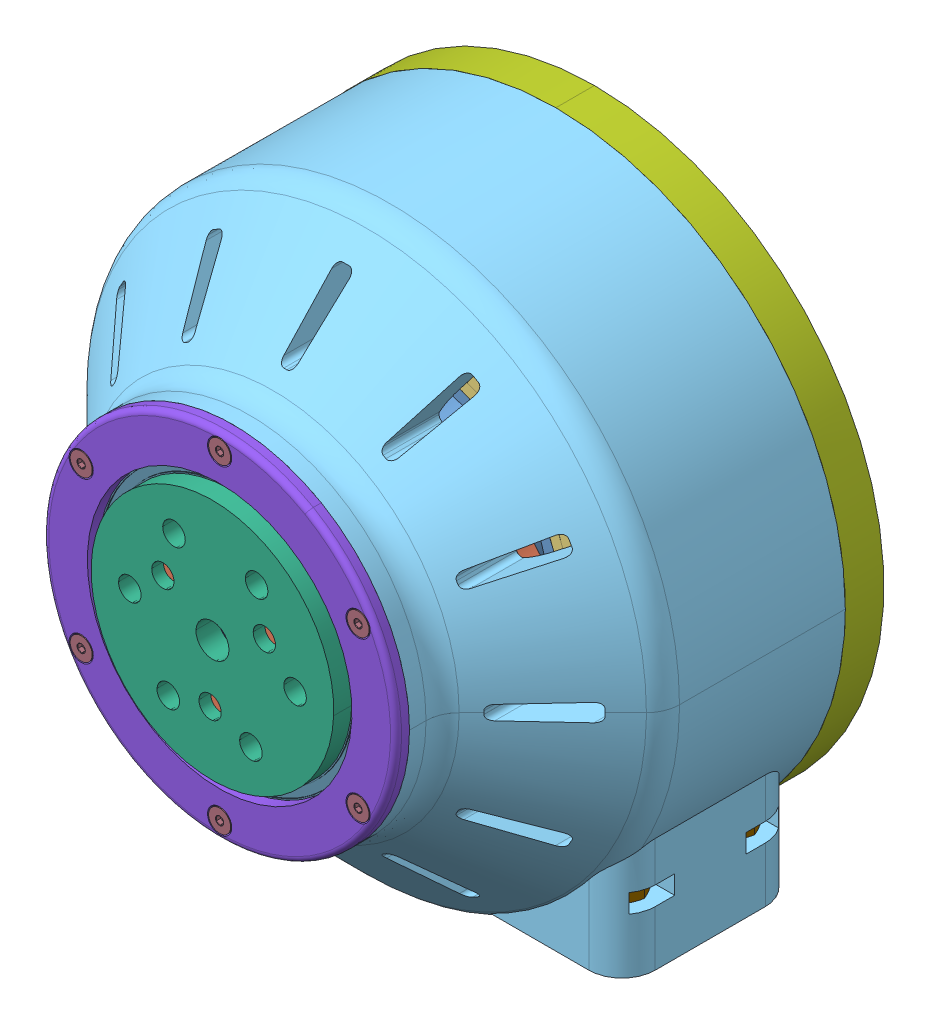
SolidWorks assembly sprydrive 9235, configuration Default. Lengths in mm.
Overall size (130.11 130.11 75.41).
71 component instances, 27 part files, 0 mates.
Components (placement in the parent):
- sprydrive 9235.STEP-1: sprydrive 9235.STEP [Default] at origin size (130.11 130.11 75.41)
  - MOTOR BACK HOUSING REV01.STEP-1: MOTOR BACK HOUSING REV01.STEP [Default] at (0 0 6) x (0.707107 0.707107 0) z (-0.707107 0.707107 0) size (92 25.2 92)
  - MOTOR ROTOR REV01_9235.STEP-1: MOTOR ROTOR REV01_9235.STEP [Default] at (0 0 6.3) x (0.001555 -0.999999 0) z (-0.999999 -0.001555 0) size (92 31.21 92)
  - MOTOR STATOR REV01.STEP-1: MOTOR STATOR REV01.STEP [Default] at (0 0 7.2) x (-0.996782 0.080159 0) z (0.080159 0.996782 0) size (81.2 19.01 81.2)
  - MOTOR SHAFT REV01_9235.STEP-1: MOTOR SHAFT REV01_9235.STEP [Default] at (0 0 3.5) x (-0.001555 0.999999 0) z (0.999999 0.001555 0) size (19.64 47.51 18.94)
  - FRAME REV07_9235.STEP-1: FRAME REV07_9235.STEP [Default] at origin size (105 105 58.55)
  - OUTPUT PLATE REV05.STEP-1: OUTPUT PLATE REV05.STEP [Default] at (0 0 58.225) x (-0.999207 0.039825 0) z (0 0 1) size (44 44 11.85)
  - BACK PLATE REV05.STEP-1: BACK PLATE REV05.STEP [Default] x (-1 0 0) z (0 -1 0) size (105 7 105)
  - BEARING COVER REV04.STEP-1: BEARING COVER REV04.STEP [Default] at (0 0 59) x (-0.5 -0.866025 0) z (0 0 1) size (64 64 2.45)
  - ADAPTER PLATE REV05.STEP-1: ADAPTER PLATE REV05.STEP [Default] at (0 0 37.5) x (-0.999999 -0.001555 0) z (0 0 1) size (37 37 3.17)
  - MAGNET HOLDER REV02.STEP-1: MAGNET HOLDER REV02.STEP [Default] at (0 0 -2) x (0.865247 0.501346 0) z (0 0 -1) size (24 24 5)
  - ENCODER MOUNT REV01.STEP-1: ENCODER MOUNT REV01.STEP [Default] x (-1 0 0) z (0 -1 0) size (35.15 5.5 30)
  - 91294A190_BLACK ALLOY STEEL FLAT-HEAD SOCKET CAP SCREW_91294A190.STEP-1: 91294A190_BLACK ALLOY STEEL FLAT-HEAD SOCKET CAP SCREW_91294A190.STEP [Default] at (-20 0 -6.6) x (-1 0 0) z (0 0 -1) size (8 8 10.01)
  - 91294A190_BLACK ALLOY STEEL FLAT-HEAD SOCKET CAP SCREW_91294A190.STEP-2: 91294A190_BLACK ALLOY STEEL FLAT-HEAD SOCKET CAP SCREW_91294A190.STEP [Default] at (0 20 -6.6) x (-1 0 0) z (0 0 -1) size (8 8 10.01)
  - 91294A190_BLACK ALLOY STEEL FLAT-HEAD SOCKET CAP SCREW_91294A190.STEP-3: 91294A190_BLACK ALLOY STEEL FLAT-HEAD SOCKET CAP SCREW_91294A190.STEP [Default] at (20 0 -6.6) x (-1 0 0) z (0 0 -1) size (8 8 10.01)
  - 93395A144_TYPE 316 SS FLAT-HEAD SOCKET CAP SCREW_93395A144.STEP-1: 93395A144_TYPE 316 SS FLAT-HEAD SOCKET CAP SCREW_93395A144.STEP [Default] at (14.0729 8.125 -12.5) x (-1 0 0) z (0 0 -1) size (4 4 10)
  - 93395A144_TYPE 316 SS FLAT-HEAD SOCKET CAP SCREW_93395A144.STEP-2: 93395A144_TYPE 316 SS FLAT-HEAD SOCKET CAP SCREW_93395A144.STEP [Default] at (-14.0729 8.125 -12.5) x (-1 0 0) z (0 0 -1) size (4 4 10)
  - 93395A144_TYPE 316 SS FLAT-HEAD SOCKET CAP SCREW_93395A144.STEP-3: 93395A144_TYPE 316 SS FLAT-HEAD SOCKET CAP SCREW_93395A144.STEP [Default] at (-14.0729 -8.125 -12.5) x (-1 0 0) z (0 0 -1) size (4 4 10)
  - 93395A144_TYPE 316 SS FLAT-HEAD SOCKET CAP SCREW_93395A144.STEP-4: 93395A144_TYPE 316 SS FLAT-HEAD SOCKET CAP SCREW_93395A144.STEP [Default] at (14.0729 -8.125 -12.5) x (-1 0 0) z (0 0 -1) size (4 4 10)
  - 6808-2RS BEARING DEEP GROOVE 40x52x7 REV02_4668K161.STEP-1: 6808-2RS BEARING DEEP GROOVE 40x52x7 REV02_4668K161.STEP [Default] at (0 0 55.5) x (0.843788 0.536676 0) z (0 0 -1) size (52 52 7)
  - AS5048A-AB-1.0-ND ENCODER BOARD.STEP-1: AS5048A-AB-1.0-ND ENCODER BOARD.STEP [Default] at (0 -6.5 -10) x (-1 0 0) z (0 1 0) size (22 2 28)
  - AS5048A-AB-1.0-ND MAGNET.STEP-1: AS5048A-AB-1.0-ND MAGNET.STEP [Default] at (0 0 -6.5) x (0.996708 0.081075 0) z (0.081075 -0.996708 0) size (6 2.5 6)
  - OUTPUT MOUNTING PLATE REV01.STEP-1: OUTPUT MOUNTING PLATE REV01.STEP [Default] at (0 0 55.05) x (0.465114 -0.885251 0) z (0 0 1) size (35 35 3.17)
  - VERSA PLANET.STEP-1: VERSA PLANET.STEP [Default] at (-8.9927 5.6811 46.35) x (-0.69895 0.715171 0) z (0 0 1) size (16.03 16.01 8)
  - VERSA PLANET.STEP-2: VERSA PLANET.STEP [Default] at (9.4163 4.9473 46.35) x (0.461046 0.887376 0) z (0 0 1) size (16.03 16.01 8)
  - VERSA PLANET.STEP-3: VERSA PLANET.STEP [Default] at (-0.4236 -10.6284 46.35) x (-0.3211 -0.947045 0) z (0 0 1) size (16.03 16.01 8)
  - VERSA RING - MODIFIED.STEP-1: VERSA RING - MODIFIED.STEP [Default] at (0 0 41.6) x (0 1 0) z (0 0 -1) size (42 42 11.32)
  - 93600A455_METRIC TYPE 316 STAINLESS STEEL DOWEL PIN_93600A455.STEP-1: 93600A455_METRIC TYPE 316 STAINLESS STEEL DOWEL PIN_93600A455.STEP [Default] at (-8.9927 5.6811 51.35) x (0 0 -1) z (0.833244 0.552906 0) size (18 4 4)
  - 93600A455_METRIC TYPE 316 STAINLESS STEEL DOWEL PIN_93600A455.STEP-2: 93600A455_METRIC TYPE 316 STAINLESS STEEL DOWEL PIN_93600A455.STEP [Default] at (9.4163 4.9473 51.35) x (0 0 -1) z (0.833244 0.552906 0) size (18 4 4)
  - 93600A455_METRIC TYPE 316 STAINLESS STEEL DOWEL PIN_93600A455.STEP-3: 93600A455_METRIC TYPE 316 STAINLESS STEEL DOWEL PIN_93600A455.STEP [Default] at (-0.4236 -10.6284 51.35) x (0 0 -1) z (-0.663244 0.748403 0) size (18 4 4)
  - 90358A002_METRIC STL ULTRA-LOW-PROFILE SCKT HEAD SCREW_90358A002.STEP-1: 90358A002_METRIC STL ULTRA-LOW-PROFILE SCKT HEAD SCREW_90358A002.STEP [Default] at (0.0241 -15.5 36.675) x (0 0 -1) z (-0.620938 -0.783859 0) size (9.01 5.5 5.5)
  - 90358A002_METRIC STL ULTRA-LOW-PROFILE SCKT HEAD SCREW_90358A002.STEP-2: 90358A002_METRIC STL ULTRA-LOW-PROFILE SCKT HEAD SCREW_90358A002.STEP [Default] at (15.5 0.0241 36.675) x (0 0 -1) z (-0.964603 -0.263707 0) size (9.01 5.5 5.5)
  - 90358A002_METRIC STL ULTRA-LOW-PROFILE SCKT HEAD SCREW_90358A002.STEP-3: 90358A002_METRIC STL ULTRA-LOW-PROFILE SCKT HEAD SCREW_90358A002.STEP [Default] at (-0.0241 15.5 36.675) x (0 0 -1) z (-0.993401 0.11469 0) size (9.01 5.5 5.5)
  - 90358A002_METRIC STL ULTRA-LOW-PROFILE SCKT HEAD SCREW_90358A002.STEP-4: 90358A002_METRIC STL ULTRA-LOW-PROFILE SCKT HEAD SCREW_90358A002.STEP [Default] at (-15.5 -0.0241 36.675) x (0 0 -1) z (-0.942672 -0.333722 0) size (9.01 5.5 5.5)
  - 93395A144_TYPE 316 SS FLAT-HEAD SOCKET CAP SCREW_93395A144.STEP-5: 93395A144_TYPE 316 SS FLAT-HEAD SOCKET CAP SCREW_93395A144.STEP [Default] at (0 29 61) size (4 4 10)
  - 93395A144_TYPE 316 SS FLAT-HEAD SOCKET CAP SCREW_93395A144.STEP-6: 93395A144_TYPE 316 SS FLAT-HEAD SOCKET CAP SCREW_93395A144.STEP [Default] at (25.1147 14.5 61) size (4 4 10)
  - 93395A144_TYPE 316 SS FLAT-HEAD SOCKET CAP SCREW_93395A144.STEP-7: 93395A144_TYPE 316 SS FLAT-HEAD SOCKET CAP SCREW_93395A144.STEP [Default] at (-25.1147 14.5 61) size (4 4 10)
  - 93395A144_TYPE 316 SS FLAT-HEAD SOCKET CAP SCREW_93395A144.STEP-8: 93395A144_TYPE 316 SS FLAT-HEAD SOCKET CAP SCREW_93395A144.STEP [Default] at (25.1147 -14.5 61) size (4 4 10)
  - 94459A110_BRASS HEAT-SET INSERT FOR PLASTIC_94459A110.STEP-1: 94459A110_BRASS HEAT-SET INSERT FOR PLASTIC_94459A110.STEP [Default] at (25.1147 14.5 56.05) x (-0.767549 -0.640991 0) z (-0.640991 0.767549 0) size (3.69 2.5 3.69)
  - 94459A110_BRASS HEAT-SET INSERT FOR PLASTIC_94459A110.STEP-2: 94459A110_BRASS HEAT-SET INSERT FOR PLASTIC_94459A110.STEP [Default] at (0 29 56.05) x (-0.593469 0.804857 0) z (0.804857 0.593469 0) size (3.69 2.5 3.69)
  - 94459A110_BRASS HEAT-SET INSERT FOR PLASTIC_94459A110.STEP-3: 94459A110_BRASS HEAT-SET INSERT FOR PLASTIC_94459A110.STEP [Default] at (0 -29 56.05) x (-0.997114 0.075912 0) z (0.075912 0.997114 0) size (3.69 2.5 3.69)
  - 94459A110_BRASS HEAT-SET INSERT FOR PLASTIC_94459A110.STEP-4: 94459A110_BRASS HEAT-SET INSERT FOR PLASTIC_94459A110.STEP [Default] at (25.1147 -14.5 56.05) x (0.079432 0.99684 0) z (0.99684 -0.079432 0) size (3.69 2.5 3.69)
  - 93395A144_TYPE 316 SS FLAT-HEAD SOCKET CAP SCREW_93395A144.STEP-9: 93395A144_TYPE 316 SS FLAT-HEAD SOCKET CAP SCREW_93395A144.STEP [Default] at (0 -49.5 -7) x (-1 0 0) z (0 0 -1) size (4 4 10)
  - 93395A144_TYPE 316 SS FLAT-HEAD SOCKET CAP SCREW_93395A144.STEP-10: 93395A144_TYPE 316 SS FLAT-HEAD SOCKET CAP SCREW_93395A144.STEP [Default] at (-42.8683 -24.75 -7) x (-1 0 0) z (0 0 -1) size (4 4 10)
  - 93395A144_TYPE 316 SS FLAT-HEAD SOCKET CAP SCREW_93395A144.STEP-11: 93395A144_TYPE 316 SS FLAT-HEAD SOCKET CAP SCREW_93395A144.STEP [Default] at (42.8683 -24.75 -7) x (-1 0 0) z (0 0 -1) size (4 4 10)
  - 93395A144_TYPE 316 SS FLAT-HEAD SOCKET CAP SCREW_93395A144.STEP-12: 93395A144_TYPE 316 SS FLAT-HEAD SOCKET CAP SCREW_93395A144.STEP [Default] at (0 49.5 -7) x (-1 0 0) z (0 0 -1) size (4 4 10)
  - 93395A144_TYPE 316 SS FLAT-HEAD SOCKET CAP SCREW_93395A144.STEP-13: 93395A144_TYPE 316 SS FLAT-HEAD SOCKET CAP SCREW_93395A144.STEP [Default] at (-42.8683 24.75 -7) x (-1 0 0) z (0 0 -1) size (4 4 10)
  - 93395A144_TYPE 316 SS FLAT-HEAD SOCKET CAP SCREW_93395A144.STEP-14: 93395A144_TYPE 316 SS FLAT-HEAD SOCKET CAP SCREW_93395A144.STEP [Default] at (42.8683 24.75 -7) x (-1 0 0) z (0 0 -1) size (4 4 10)
  - 94459A110_BRASS HEAT-SET INSERT FOR PLASTIC_94459A110.STEP-5: 94459A110_BRASS HEAT-SET INSERT FOR PLASTIC_94459A110.STEP [Default] at (42.8683 -24.75 2.5) x (0.239904 0.970797 0) z (-0.970797 0.239904 0) size (3.69 2.5 3.69)
  - 94459A110_BRASS HEAT-SET INSERT FOR PLASTIC_94459A110.STEP-6: 94459A110_BRASS HEAT-SET INSERT FOR PLASTIC_94459A110.STEP [Default] at (0 49.5 2.5) x (0.239904 0.970797 0) z (-0.970797 0.239904 0) size (3.69 2.5 3.69)
  - 94459A110_BRASS HEAT-SET INSERT FOR PLASTIC_94459A110.STEP-7: 94459A110_BRASS HEAT-SET INSERT FOR PLASTIC_94459A110.STEP [Default] at (42.8683 24.75 2.5) x (0.239904 0.970797 0) z (-0.970797 0.239904 0) size (3.69 2.5 3.69)
  - 94459A110_BRASS HEAT-SET INSERT FOR PLASTIC_94459A110.STEP-8: 94459A110_BRASS HEAT-SET INSERT FOR PLASTIC_94459A110.STEP [Default] at (-42.8683 -24.75 2.5) x (0.239904 0.970797 0) z (-0.970797 0.239904 0) size (3.69 2.5 3.69)
  - 94459A110_BRASS HEAT-SET INSERT FOR PLASTIC_94459A110.STEP-9: 94459A110_BRASS HEAT-SET INSERT FOR PLASTIC_94459A110.STEP [Default] at (0 -49.5 2.5) x (0.239904 0.970797 0) z (-0.970797 0.239904 0) size (3.69 2.5 3.69)
  - 94459A110_BRASS HEAT-SET INSERT FOR PLASTIC_94459A110.STEP-10: 94459A110_BRASS HEAT-SET INSERT FOR PLASTIC_94459A110.STEP [Default] at (-42.8683 24.75 2.5) x (0.239904 0.970797 0) z (-0.970797 0.239904 0) size (3.69 2.5 3.69)
  - 91294A190_BLACK ALLOY STEEL FLAT-HEAD SOCKET CAP SCREW_91294A190.STEP-4: 91294A190_BLACK ALLOY STEEL FLAT-HEAD SOCKET CAP SCREW_91294A190.STEP [Default] at (0 -20 -6.6) x (-1 0 0) z (0 0 -1) size (8 8 10.01)
  - 93395A144_TYPE 316 SS FLAT-HEAD SOCKET CAP SCREW_93395A144.STEP-15: 93395A144_TYPE 316 SS FLAT-HEAD SOCKET CAP SCREW_93395A144.STEP [Default] at (0 -29 61) size (4 4 10)
  - 93395A144_TYPE 316 SS FLAT-HEAD SOCKET CAP SCREW_93395A144.STEP-16: 93395A144_TYPE 316 SS FLAT-HEAD SOCKET CAP SCREW_93395A144.STEP [Default] at (-25.1147 -14.5 61) size (4 4 10)
  - 90710A025_TYPE 18-8 SS THIN HEX NUT - DIN 439B_90710A025.STEP-1: 90710A025_TYPE 18-8 SS THIN HEX NUT - DIN 439B_90710A025.STEP [Default] at (9 -5.5 -12.3) x (-0.866025 0.5 0) z (-0.5 -0.866025 0) size (5.78 1.62 5.78)
  - 90710A025_TYPE 18-8 SS THIN HEX NUT - DIN 439B_90710A025.STEP-2: 90710A025_TYPE 18-8 SS THIN HEX NUT - DIN 439B_90710A025.STEP [Default] at (-9 -5.5 -12.3) x (-0.866025 0.5 0) z (-0.5 -0.866025 0) size (5.78 1.62 5.78)
  - 90710A025_TYPE 18-8 SS THIN HEX NUT - DIN 439B_90710A025.STEP-3: 90710A025_TYPE 18-8 SS THIN HEX NUT - DIN 439B_90710A025.STEP [Default] at (-9 5.5 -12.3) x (-0.866025 0.5 0) z (-0.5 -0.866025 0) size (5.78 1.62 5.78)
  - 90710A025_TYPE 18-8 SS THIN HEX NUT - DIN 439B_90710A025.STEP-4: 90710A025_TYPE 18-8 SS THIN HEX NUT - DIN 439B_90710A025.STEP [Default] at (9 5.5 -12.3) x (-0.866025 0.5 0) z (-0.5 -0.866025 0) size (5.78 1.62 5.78)
  - NMB L2112KK BEARING.STEP-1: NMB L2112KK BEARING.STEP [Default] at (0 0 19.2) x (0.90792 -0.419144 0) z (0 0 1) size (21 21 5)
  - NMB L2112KK BEARING.STEP-2: NMB L2112KK BEARING.STEP [Default] at (0 0 3.5) x (0.990401 -0.138221 0) z (0 0 1) size (21 21 5)
  - VERSA CARRIER.STEP-1: VERSA CARRIER.STEP [Default] at (0 0 52.7) x (0.534093 0.845426 0) z (0 0 1) size (34.7 34.7 4.7)
  - VERSA SUN GEAR, 12T.STEP-1: VERSA SUN GEAR, 12T.STEP [Default] at (0 0 43.85) x (0.939988 -0.341209 0) z (0 0 1) size (14.47 14.47 12.71)
  - 90592A090_STEEL HEX NUT_90592A090.STEP-1: 90592A090_STEEL HEX NUT_90592A090.STEP [Default] at (40 -34.4 28) x (0 0 -1) z (1 0 0) size (8.09 3.22 8.1)
  - 90592A090_STEEL HEX NUT_90592A090.STEP-2: 90592A090_STEEL HEX NUT_90592A090.STEP [Default] at (40 -34.4 8) x (0 0 -1) z (1 0 0) size (8.09 3.22 8.1)
  - 90592A090_STEEL HEX NUT_90592A090.STEP-3: 90592A090_STEEL HEX NUT_90592A090.STEP [Default] at (-40 -34.2 8) x (0 0 1) z (1 0 0) size (8.09 3.22 8.1)
  - 90592A090_STEEL HEX NUT_90592A090.STEP-4: 90592A090_STEEL HEX NUT_90592A090.STEP [Default] at (-40 -34.4 28) x (0 0 1) z (-1 0 0) size (8.09 3.22 8.1)
  - 94459A110_BRASS HEAT-SET INSERT FOR PLASTIC_94459A110.STEP-11: 94459A110_BRASS HEAT-SET INSERT FOR PLASTIC_94459A110.STEP [Default] at (-25.1147 -14.5 56.05) x (-0.532301 0.846555 0) z (0.846555 0.532301 0) size (3.69 2.5 3.69)
  - 94459A110_BRASS HEAT-SET INSERT FOR PLASTIC_94459A110.STEP-12: 94459A110_BRASS HEAT-SET INSERT FOR PLASTIC_94459A110.STEP [Default] at (-25.1147 14.5 56.05) x (-0.588465 0.808522 0) z (0.808522 0.588465 0) size (3.69 2.5 3.69)
